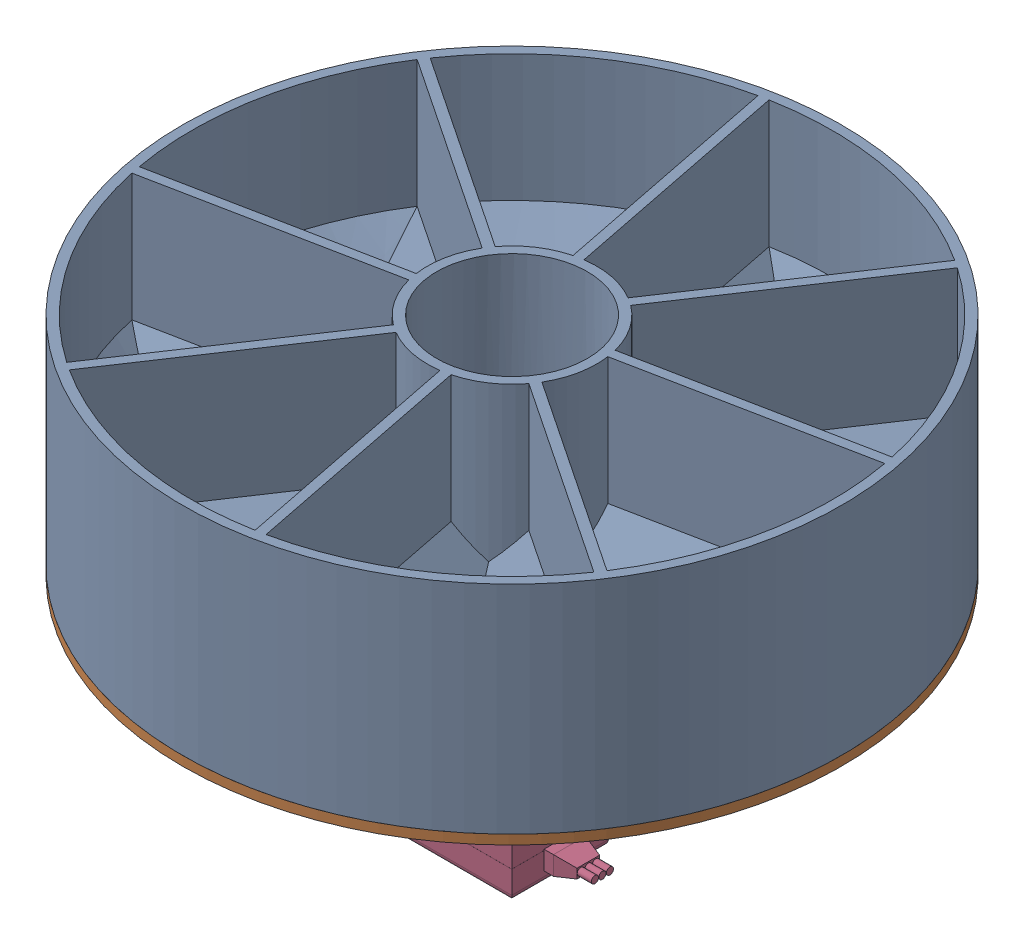
SolidWorks assembly Magazine, configuration Default. Lengths in mm.
Overall size (194.18 97.7 194.18).
4 component instances, 4 part files, 10 mates.
Components (placement in the parent):
- Magazine Cover-1: Magazine Cover [Default] at (-85.3854 -21.0036 34.5287) x (-0.831534 0 -0.555474) z (0.555474 0 -0.831534) size (140 46 140)
- Bottom cover-1: Bottom cover [Default] at (-85.3854 -24.0036 34.5287) x (0.999999 0 -0.001148) z (0.001148 0 0.999999) size (140 6 140)
- Servo connector-1: Servo connector [Default] at (-85.3854 -22.0036 34.5287) x (0.996622 0 0.082124) z (-0.082124 0 0.996622) size (32 20 27.98)
- LF20MG-1: LF20MG [Default] at (-95.5354 -73.7036 34.5287) x (0 0 1) z (-1 0 0) size (20.52 44.75 56.6)
Mates (geometry in assembly coordinates):
- Coincident1: coincident anti-aligned: plane of Magazine Cover-1 through (-85.3854 -22.0036 34.5287) normal (0 -1 0); plane of Bottom cover-1 through (-85.3854 -22.0036 34.5287) normal (0 1 0)
- Concentric1: concentric aligned: cylinder of Magazine Cover-1 through (-85.3854 23.9964 34.5287) axis (0 -1 0) radius 70; cylinder of Bottom cover-1 through (-85.3854 -22.0036 34.5287) axis (0 -1 0) radius 70
- Coincident2: coincident aligned: plane of Magazine Cover-1 through (-85.3854 -22.0036 34.5287) normal (0 -1 0); plane of Servo connector-1 through (-85.3854 -22.0036 34.5287) normal (0 -1 0)
- Coincident3: coincident anti-aligned: plane of Magazine Cover-1 through (-101.3513 -22.0036 33.4841) normal (0.896822 0 -0.442392); plane of Servo connector-1 through (-97.8121 -12.0036 40.6587) normal (-0.896822 0 0.442392)
- Coincident4: coincident anti-aligned: plane of Magazine Cover-1 through (-78.3071 -22.0036 48.8779) normal (-0.831534 0 -0.555474); plane of Servo connector-1 through (-73.8633 -12.0036 42.2256) normal (0.831534 0 0.555474)
- Concentric2: concentric aligned: cylinder of Servo connector-1 through (-85.3854 -12.0036 34.5287) axis (0 -1 0) radius 2.925; cylinder of LF20MG-1 through (-85.3854 -28.9536 34.5287) axis (0 -1 0) radius 2.925
- Distance1: distance = 1 mm anti-aligned: plane of Servo connector-1 through (-85.3854 -32.0036 34.5287) normal (0 -1 0); plane of LF20MG-1 through (-95.5354 -33.0036 34.5287) normal (0 1 0)
- Concentric3: concentric aligned: cylinder of Bottom cover-1 through (-85.3854 -22.0036 34.5287) axis (0 -1 0) radius 70; cylinder of Magazine door-1 through (-85.3854 -20.0036 34.5287) axis (0 -1 0) radius 100
- Coincident7: coincident aligned: plane of Bottom cover-1 through (-85.3854 -22.0036 34.5287) normal (0 1 0); plane of Magazine door-1 through (-85.3854 -20.0036 34.5287) normal (0 1 0)
- Parallel2: parallel aligned: plane of LF20MG-1 through (-95.5354 -73.7036 44.7787) normal (0 0 1)
